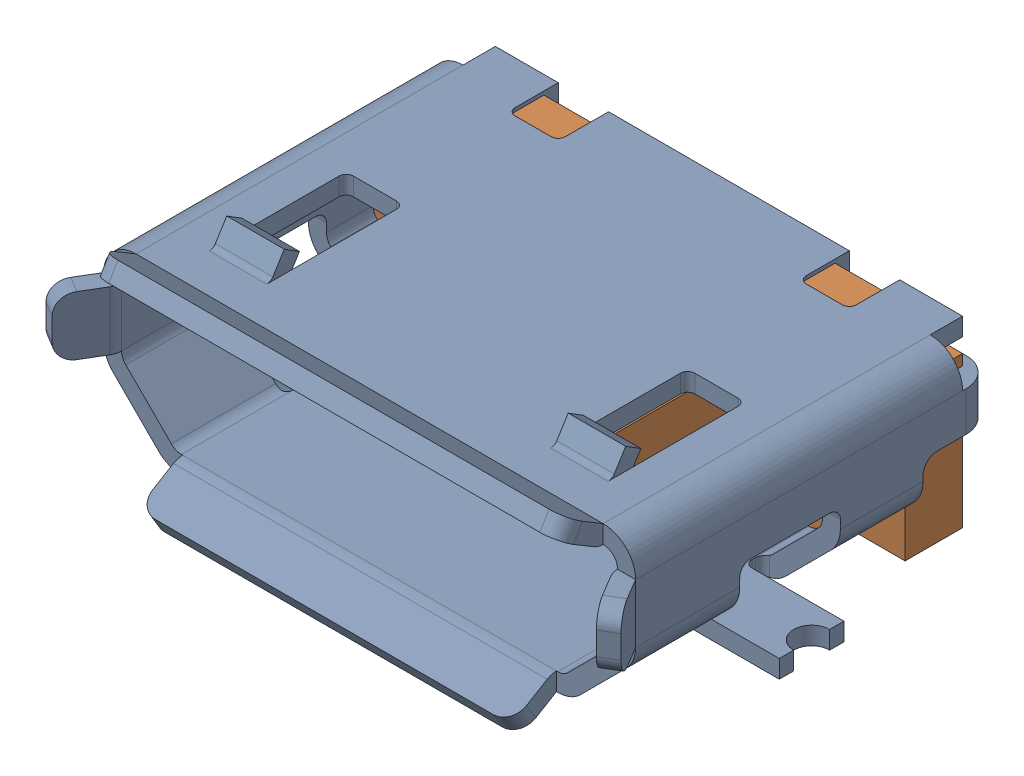
SolidWorks assembly micro usb, configuration Default. Lengths in mm.
Overall size (8.01 3.25 5.93).
7 component instances, 3 part files, 0 mates.
Components (placement in the parent):
- micro usb shell-1: micro usb shell [Default] at origin size (8.01 2.95 5.63)
- micro usb internal-1: micro usb internal [Default] at (0 -0.25 0) size (6.9 2.9 4)
- micro usb contact-1: micro usb contact [Default] at (1.3 -0.25 -0.1) size (0.2 1.3 4.4)
- micro usb contact-2: micro usb contact [Default] at (0.65 -0.25 -0.1) size (0.2 1.3 4.4)
- micro usb contact-3: micro usb contact [Default] at (0 -0.25 -0.1) size (0.2 1.3 4.4)
- micro usb contact-4: micro usb contact [Default] at (-0.65 -0.25 -0.1) size (0.2 1.3 4.4)
- micro usb contact-5: micro usb contact [Default] at (-1.3 -0.25 -0.1) size (0.2 1.3 4.4)
